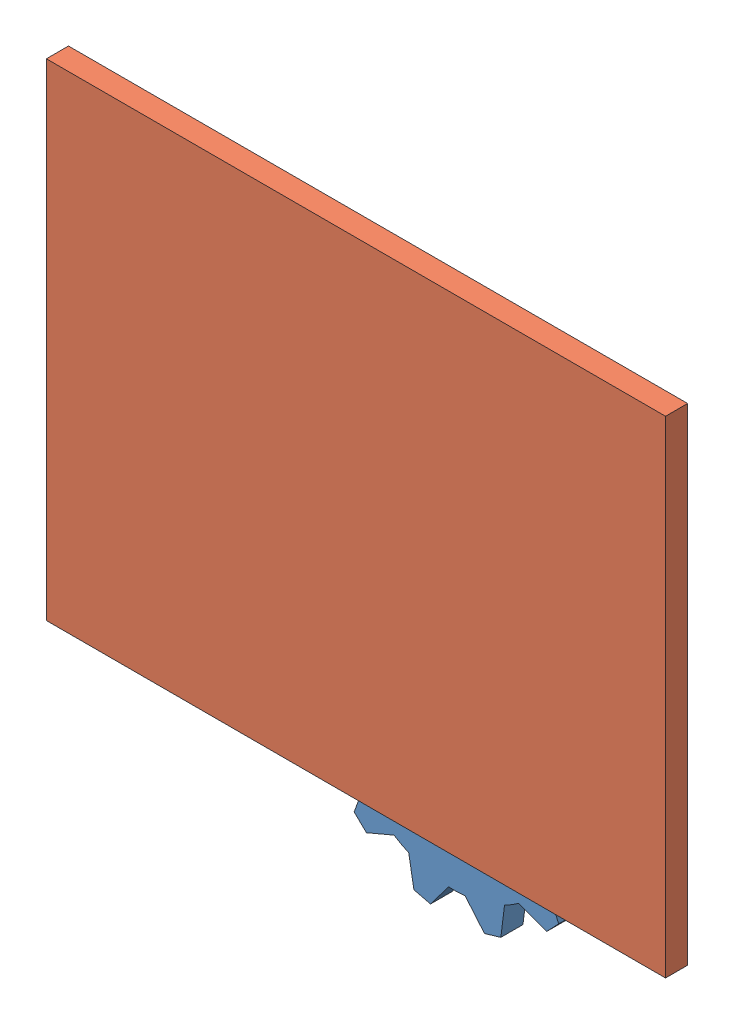
SolidWorks assembly Test_5, configuration Default. Lengths in mm.
Overall size (285.47 269.91 20).
3 component instances, 2 part files, 7 mates.
Components (placement in the parent):
- Gear_1-3: Gear_1 [Default] at (-105.6577 26.5914 -10) x (0.958794 0.284101 0) z (0 0 1) size (123.1 123.1 10)
- Gear_1-4: Gear_1 [Default] at (-213.1724 71.5073 -10) x (0.193443 -0.981111 0) z (0 0 1) size (123.1 123.1 10)
- Background-1: Background [Default] at (-164.4985 122.0365 0) size (280 220 10)
Mates (geometry in assembly coordinates):
- Concentric1: concentric anti-aligned: circle of Gear_1-4
- Concentric2: concentric anti-aligned: circle of Gear_1-3
- Coincident3: coincident anti-aligned: plane of Background-1 through (-164.4985 122.0365 0) normal (0 0 -1)
- Coincident4: coincident aligned: plane of Background-1 through (0 220 10) normal (1 0 0)
- Coincident5: coincident anti-aligned: plane of Background-1 through (-280 0 10) normal (0 -1 0)
- Coincident6: coincident anti-aligned: plane of Gear_1-4 through (-213.1724 71.5073 0) normal (0 0 1); plane of Background-1 through (-164.4985 122.0365 0) normal (0 0 -1)
- Coincident7: coincident anti-aligned: plane of Gear_1-3 through (-105.6577 26.5914 0) normal (0 0 1); plane of Background-1 through (-164.4985 122.0365 0) normal (0 0 -1)
